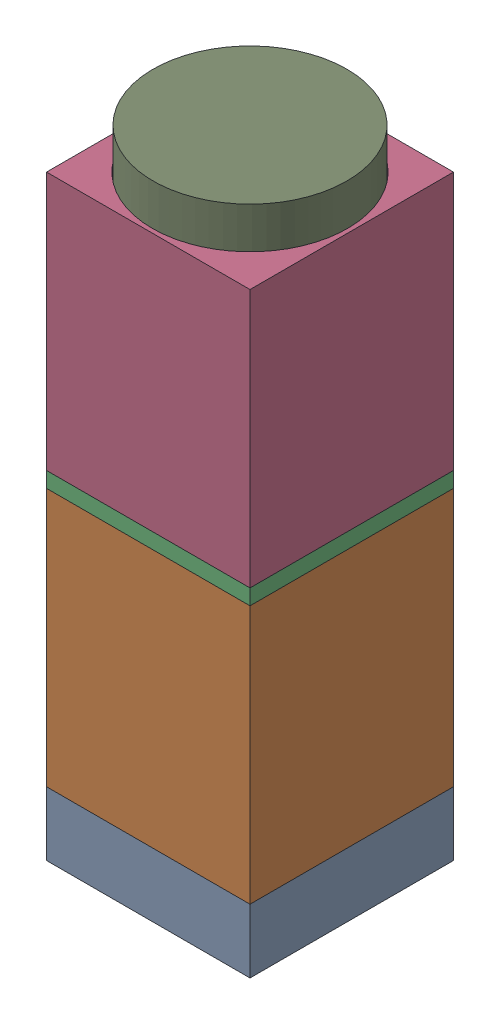
SolidWorks assembly SingleCell, configuration Default. Lengths in mm.
Overall size (6.17 15.65 6.17).
9 component instances, 8 part files, 19 mates.
Components (placement in the parent):
- PCB-1: PCB [Default] at (-4.0841 -0.8063 2.7029) size (5 1.57 5)
- MagneticSheilding-1: MagneticSheilding [Default] at (-4.0841 0.7637 2.7029) size (5 6.35 5)
- SiliconeMembrane-1: SiliconeMembrane [Default] at (-4.0841 7.1137 2.7029) size (5 0.38 5)
- DelrinGuide-1: DelrinGuide [Default] at (-4.0841 7.4947 2.7029) size (5 6.35 5)
- Magnet_2mm-1: Magnet_2mm [Default] at (-1.5841 7.4947 0.2029) x (0.996124 0 -0.087961) z (0.087961 0 0.996124) size (2 1 2)
- Magnet_2mm-2: Magnet_2mm [Default] at (-1.5841 6.1137 0.2029) x (0.473208 0 -0.880951) z (0.880951 0 0.473208) size (2 1 2)
- Core_SP43-221K-1: Core_SP43-221K [Default] at (-1.5841 0.7637 0.2029) size (4.5 3.2 4)
- Coil_SP43-221K-1: Coil_SP43-221K [Default] at (-1.5841 1.5137 0.2029) size (3.9 1.7 3.9)
- AcetalDowelRod-1: AcetalDowelRod [Default] at (-1.5841 8.4947 0.2029) x (0.931359 0 -0.364103) z (0.364103 0 0.931359) size (4.76 6.35 4.76)
Mates (geometry in assembly coordinates):
- Coincident1: coincident anti-aligned: plane of PCB-1 through (-4.0841 0.7637 2.7029) normal (0 1 0); plane of MagneticSheilding-1 through (-4.0841 0.7637 2.7029) normal (0 -1 0)
- Coincident2: coincident aligned: line of PCB-1 through (0.9159 0.7637 -2.2971) axis (-1 0 0); line of MagneticSheilding-1 through (0.9159 0.7637 -2.2971) axis (-1 0 0)
- Coincident3: coincident aligned: line of PCB-1 through (-4.0841 0.7637 -2.2971) axis (0 0 1); line of MagneticSheilding-1 through (-4.0841 0.7637 -2.2971) axis (0 0 1)
- Coincident4: coincident anti-aligned: plane of MagneticSheilding-1 through (-4.0841 7.1137 2.7029) normal (0 1 0); plane of SiliconeMembrane-1 through (-4.0841 7.1137 2.7029) normal (0 -1 0)
- Coincident5: coincident anti-aligned: line of MagneticSheilding-1 through (-4.0841 7.1137 -2.2971) axis (0 0 1); line of SiliconeMembrane-1 through (-4.0841 7.1137 2.7029) axis (0 0 -1)
- Coincident6: coincident aligned: line of MagneticSheilding-1 through (-4.0841 7.1137 2.7029) axis (1 0 0); line of SiliconeMembrane-1 through (-4.0841 7.1137 2.7029) axis (1 0 0)
- Coincident7: coincident anti-aligned: plane of SiliconeMembrane-1 through (-4.0841 7.4947 2.7029) normal (0 1 0); plane of DelrinGuide-1 through (-4.0841 7.4947 2.7029) normal (0 -1 0)
- Coincident8: coincident aligned: line of SiliconeMembrane-1 through (-4.0841 7.4947 2.7029) axis (1 0 0); line of DelrinGuide-1 through (-4.0841 7.4947 2.7029) axis (1 0 0)
- Coincident9: coincident aligned: line of SiliconeMembrane-1 through (0.9159 7.4947 2.7029) axis (0 0 -1); line of DelrinGuide-1 through (0.9159 7.4947 2.7029) axis (0 0 -1)
- Concentric1: concentric aligned: circle of DelrinGuide-1; circle of Magnet_2mm-1
- Concentric2: concentric aligned: circle of DelrinGuide-1; circle of Magnet_2mm-2
- Coincident10: coincident anti-aligned: plane of SiliconeMembrane-1 through (-4.0841 7.1137 2.7029) normal (0 -1 0); plane of Magnet_2mm-2 through (-1.5841 7.1137 0.2029) normal (0 1 0)
- Coincident11: coincident anti-aligned: plane of SiliconeMembrane-1 through (-4.0841 7.4947 2.7029) normal (0 1 0); plane of Magnet_2mm-1 through (-1.5841 7.4947 0.2029) normal (0 -1 0)
- Coincident12: coincident aligned: circle of Core_SP43-221K-1; circle of Coil_SP43-221K-1
- Concentric3: concentric aligned: circle of DelrinGuide-1; circle of Core_SP43-221K-1
- Coincident13: coincident anti-aligned: plane of PCB-1 through (-4.0841 0.7637 2.7029) normal (0 1 0); plane of Core_SP43-221K-1 through (-1.5841 0.7637 0.2029) normal (0 -1 0)
- Parallel1: parallel aligned: line of PCB-1 through (0.9159 0.7637 -2.2971) axis (-1 0 0); line of Core_SP43-221K-1 through (-0.5533 3.9637 -1.7971) axis (-1 0 0)
- Concentric4: concentric aligned: circle of DelrinGuide-1; circle of AcetalDowelRod-1
- Coincident15: coincident anti-aligned: plane of Magnet_2mm-1 through (-1.5841 8.4947 0.2029) normal (0 1 0); plane of AcetalDowelRod-1 through (-1.5841 8.4947 0.2029) normal (0 -1 0)
